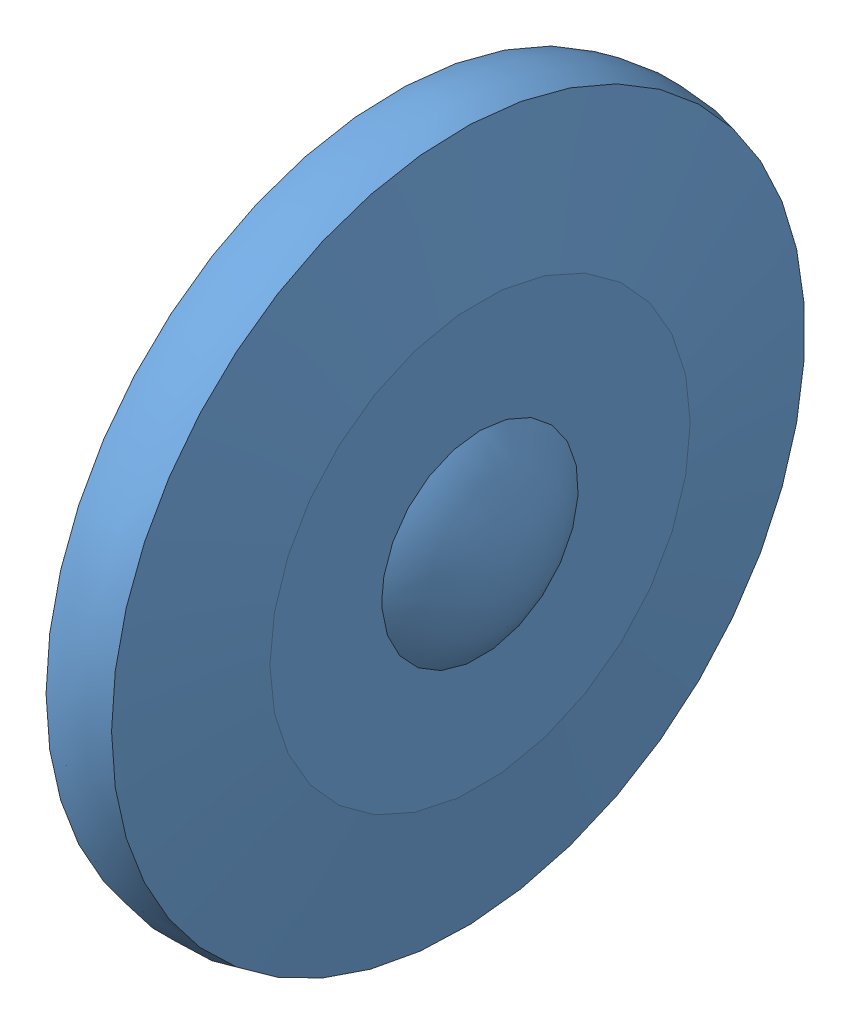
SolidWorks assembly Каток 129(47) в сборе, configuration 00. Lengths in mm.
Overall size (35.7 129 129).
4 component instances, 4 part files, 6 mates.
Components (placement in the parent):
- Каток 129(47)-1: Каток 129(47) [--] at origin size (35 129 129)
- Подшипник ГОСТ 8338-75 -1: Подшипник ГОСТ 8338-75  [Подшипник 204 ГОСТ 8338-75] at (-1 0 0) x (1 0 0) z (0 -0.327433 -0.944874) size (14 47 47)
- Стопор внутренний до 165мм (ГОСТ 13943-86)-1: Стопор внутренний до 165мм (ГОСТ 13943-86) [Кольцо 47] at (-8 0 0) x (0 0.910839 0.412761) z (-1 0 0) size (49.5 51.2 1.7)
- Сальник 47х20-1: Сальник 47х20 [--] at (-9.7 0 0) x (-1 0 0) z (0 0.937697 -0.347453) size (10 47 47)
Mates (geometry in assembly coordinates):
- Совпадение1: coincident: plane of Каток 129(47)-1 through (6 18 0) normal (-1 0 0); plane of Подшипник ГОСТ 8338-75 -1 through (6 -17.4802 6.0575) normal (1 0 0)
- Концентричный1: concentric: cylinder of Каток 129(47)-1 through (12.9072 0 0) axis (-1 0 0) radius 23.5; cylinder of Подшипник ГОСТ 8338-75 -1 through (-1001 0 0) axis (-1 0 0) radius 23.5
- Совпадение2: coincident: plane of Подшипник ГОСТ 8338-75 -1 through (-8 -17.4802 6.0575) normal (-1 0 0); plane of Стопор внутренний до 165мм (ГОСТ 13943-86)-1 through (-8 -16.1081 6.0839) normal (1 0 0)
- Концентричный2: concentric: cylinder of Каток 129(47)-1 through (12.9072 0 0) axis (-1 0 0) radius 25.5; cylinder of Стопор внутренний до 165мм (ГОСТ 13943-86)-1 through (-9.7 0 0) axis (1 0 0) radius 24.75
- Совпадение3: coincident: plane of Стопор внутренний до 165мм (ГОСТ 13943-86)-1 through (-9.7 -16.1081 6.0839) normal (-1 0 0); plane of Сальник 47х20-1 through (-9.7 7.644 20.6293) normal (1 0 0)
- Концентричный3: concentric: cylinder of Каток 129(47)-1 through (12.9072 0 0) axis (-1 0 0) radius 23.5; cylinder of Сальник 47х20-1 through (990.3 0 0) axis (1 0 0) radius 23.5
